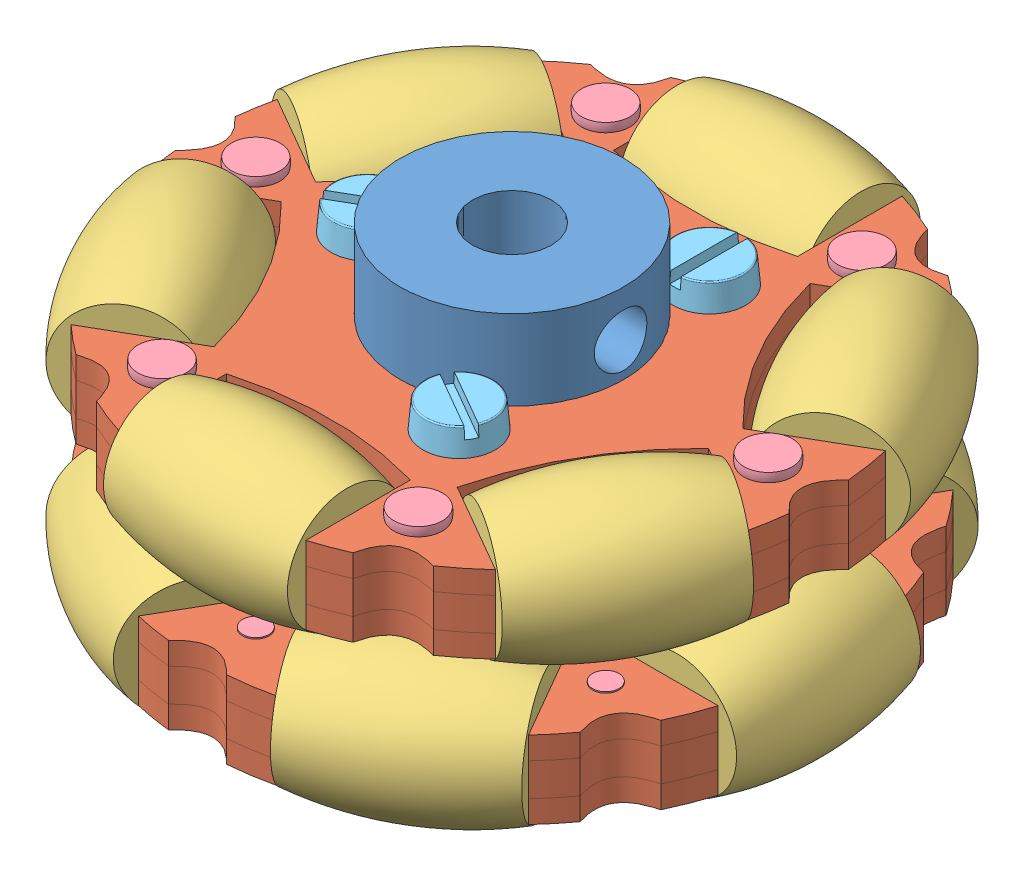
SolidWorks assembly 2寸全向轮1, configuration 默认. Lengths in mm.
Overall size (65.85 26.41 65.85).
35 component instances, 5 part files, 14 mates.
Components (placement in the parent):
- 法兰（新）-1: 法兰（新） [默认] at (1.0243 -5.9767 28) size (28 22 28)
- 2mm全向轮-1: 2mm全向轮 [默认] at (11.1029 12.5733 31.6277) x (0.866025 0 0.5) z (0 1 0) size (52.67 52.62 13.52)
  - 2mm全向轮片1-1: 2mm全向轮片1 [默认] at (-10.5422 -1.8976 -13.55) x (0 -1 0) z (0 0 1) size (47.34 45.39 5.9)
  - 从动-1: 从动 [默认] at (-10.1553 -1.8976 -5.0249) x (0 -1 0) z (0.265082 0 0.964226) size (14 11 11)
  - 从动-13: 从动 [默认] at (-10.3488 -2.2327 -5.0249) x (-0.866025 -0.5 0) z (0.132541 -0.229568 0.964226) size (14 11 11)
  - 从动-14: 从动 [默认] at (-10.7357 -2.2327 -5.0249) x (-0.866025 0.5 0) z (-0.132541 -0.229568 0.964226) size (14 11 11)
  - 从动-15: 从动 [默认] at (-10.9291 -1.8976 -5.0249) x (0 1 0) z (-0.265082 0 0.964226) size (14 11 11)
  - 从动-16: 从动 [默认] at (-10.7357 -1.5625 -5.0249) x (0.866025 0.5 0) z (-0.132541 0.229568 0.964226) size (14 11 11)
  - 从动-17: 从动 [默认] at (-10.3488 -1.5625 -5.0249) x (0.866025 -0.5 0) z (0.132541 0.229568 0.964226) size (14 11 11)
- 2mm全向轮-2: 2mm全向轮 [默认] at (7.9388 1.6733 36.181) x (0.5 0 0.866025) z (0 1 0) size (52.67 52.62 13.52)
  - 2mm全向轮片1-1: 2mm全向轮片1 [默认] at (-10.5422 -1.8976 -13.55) x (0 -1 0) z (0 0 1) size (47.34 45.39 5.9)
  - 从动-1: 从动 [默认] at (-10.1553 -1.8976 -5.0249) x (0 -1 0) z (0.265082 0 0.964226) size (14 11 11)
  - 从动-13: 从动 [默认] at (-10.3488 -2.2327 -5.0249) x (-0.866025 -0.5 0) z (0.132541 -0.229568 0.964226) size (14 11 11)
  - 从动-14: 从动 [默认] at (-10.7357 -2.2327 -5.0249) x (-0.866025 0.5 0) z (-0.132541 -0.229568 0.964226) size (14 11 11)
  - 从动-15: 从动 [默认] at (-10.9291 -1.8976 -5.0249) x (0 1 0) z (-0.265082 0 0.964226) size (14 11 11)
  - 从动-16: 从动 [默认] at (-10.7357 -1.5625 -5.0249) x (0.866025 0.5 0) z (-0.132541 0.229568 0.964226) size (14 11 11)
  - 从动-17: 从动 [默认] at (-10.3488 -1.5625 -5.0249) x (0.866025 -0.5 0) z (0.132541 0.229568 0.964226) size (14 11 11)
- thin head rivets gb-1: thin head rivets gb [GB_CONNECTING_PIECE_RIVET_THR 2X6] at (17.9118 -12.5567 18.25) x (0 1 0) z (-0.99315 0 -0.116849) size (6.68 3.74 3.74)
- thin head rivets gb-3: thin head rivets gb [GB_CONNECTING_PIECE_RIVET_THR 2X6] at (17.9118 -12.5567 37.75) x (0 1 0) z (-0.395381 0 -0.918517) size (6.68 3.74 3.74)
- thin head rivets gb-4: thin head rivets gb [GB_CONNECTING_PIECE_RIVET_THR 2X6] at (1.0243 -12.5567 47.5) x (0 1 0) z (0.597769 0 -0.801668) size (6.68 3.74 3.74)
- thin head rivets gb-5: thin head rivets gb [GB_CONNECTING_PIECE_RIVET_THR 2X6] at (-15.8632 -12.5567 37.75) x (0 1 0) z (0.99315 0 0.116849) size (6.68 3.74 3.74)
- thin head rivets gb-6: thin head rivets gb [GB_CONNECTING_PIECE_RIVET_THR 2X6] at (-15.8632 -12.5567 18.25) x (0 1 0) z (0.395381 0 0.918517) size (6.68 3.74 3.74)
- thin head rivets gb-7: thin head rivets gb [GB_CONNECTING_PIECE_RIVET_THR 2X6] at (1.0243 -12.5567 8.5) x (0 1 0) z (-0.597769 0 0.801668) size (6.68 3.74 3.74)
- thin head rivets gb-9: thin head rivets gb [GB_CONNECTING_PIECE_RIVET_THR 2X6] at (-18.4757 5.6033 28) x (0 -1 0) z (-0.795368 0 -0.606127) size (6.68 3.74 3.74)
- thin head rivets gb-11: thin head rivets gb [GB_CONNECTING_PIECE_RIVET_THR 2X6] at (-8.7257 5.6033 11.1125) x (0 -1 0) z (0.127237 0 -0.991872) size (6.68 3.74 3.74)
- thin head rivets gb-12: thin head rivets gb [GB_CONNECTING_PIECE_RIVET_THR 2X6] at (10.7743 5.6033 11.1125) x (0 -1 0) z (0.922605 0 -0.385745) size (6.68 3.74 3.74)
- thin head rivets gb-13: thin head rivets gb [GB_CONNECTING_PIECE_RIVET_THR 2X6] at (20.5243 5.6033 28) x (0 -1 0) z (0.795368 0 0.606127) size (6.68 3.74 3.74)
- thin head rivets gb-14: thin head rivets gb [GB_CONNECTING_PIECE_RIVET_THR 2X6] at (10.7743 5.6033 44.8875) x (0 -1 0) z (-0.127237 0 0.991872) size (6.68 3.74 3.74)
- thin head rivets gb-15: thin head rivets gb [GB_CONNECTING_PIECE_RIVET_THR 2X6] at (-8.7257 5.6033 44.8875) x (0 -1 0) z (-0.922605 0 0.385745) size (6.68 3.74 3.74)
- slotted cheese head screw_iso-1: slotted cheese head screw_iso [ISO 1207 - M3 x 10 - 10N] at (6.5243 6.9233 18.4737) x (0 -1 0) z (0 0 1) size (12.01 5.5 5.5)
- slotted cheese head screw_iso-2: slotted cheese head screw_iso [ISO 1207 - M3 x 10 - 10N] at (6.5243 6.9233 37.5263) x (0 -1 0) z (-0.866025 0 -0.5) size (12.01 5.5 5.5)
- slotted cheese head screw_iso-3: slotted cheese head screw_iso [ISO 1207 - M3 x 10 - 10N] at (-9.9757 6.9233 28) x (0 -1 0) z (0.866025 0 -0.5) size (12.01 5.5 5.5)
- slotted cheese head screw_iso-4: slotted cheese head screw_iso [ISO 1207 - M3 x 10 - 10N] at (10.5506 -13.8767 22.5) x (0 1 0) z (0.694913 0 -0.719094) size (12.01 5.5 5.5)
- slotted cheese head screw_iso-6: slotted cheese head screw_iso [ISO 1207 - M3 x 10 - 10N] at (1.0243 -13.8767 39) x (0 1 0) z (0.275298 0 0.961359) size (12.01 5.5 5.5)
- slotted cheese head screw_iso-7: slotted cheese head screw_iso [ISO 1207 - M3 x 10 - 10N] at (-8.502 -13.8767 22.5) x (0 1 0) z (-0.97021 0 -0.242265) size (12.01 5.5 5.5)
Mates (geometry in assembly coordinates):
- 同心1: concentric anti-aligned: cylinder of 法兰（新）-1 through (1.0243 -10.9767 28) axis (0 1 0) radius 8.5; cylinder of 2mm全向轮-1/2mm全向轮片1-1 through (1.0243 3.2233 28) axis (0 -1 0) radius 8.5
- 重合1: coincident anti-aligned: plane of 法兰（新）-1 through (1.0243 -0.9767 28) normal (0 1 0); plane of 2mm全向轮-1/2mm全向轮片1-1 through (1.0243 -0.9767 28) normal (0 -1 0)
- 同心2: concentric aligned: cylinder of 法兰（新）-1 through (6.5243 -0.9767 18.4737) axis (0 -1 0) radius 1.5; cylinder of 2mm全向轮-1/2mm全向轮片1-1 through (6.5243 9.0233 18.4737) axis (0 -1 0) radius 1.5
- 同心3: concentric anti-aligned: cylinder of 法兰（新）-1 through (1.0243 -10.9767 28) axis (0 1 0) radius 8.5; cylinder of 2mm全向轮-2/2mm全向轮片1-1 through (1.0243 -7.6767 28) axis (0 -1 0) radius 8.5
- 重合2: coincident anti-aligned: plane of 法兰（新）-1 through (1.0243 -5.9767 28) normal (0 -1 0); plane of 2mm全向轮-2/2mm全向轮片1-1 through (1.0243 -5.9767 28) normal (0 1 0)
- 同心6: concentric anti-aligned: cylinder of 2mm全向轮-2/2mm全向轮片1-1 through (17.9118 -26.4767 18.25) axis (0 1 0) radius 1; cylinder of thin head rivets gb-1 through (17.9118 -14.875 18.25) axis (0 -1 0) radius 1
- 重合4: coincident anti-aligned: plane of 2mm全向轮-2/2mm全向轮片1-1 through (1.0243 -11.8767 28) normal (0 -1 0); plane of thin head rivets gb-1 through (18.1267 -11.8767 16.4238) normal (0 1 0)
- 同心7: concentric aligned: cylinder of 法兰（新）-1 through (-8.502 -0.9767 22.5) axis (0 -1 0) radius 1.5; cylinder of 2mm全向轮-2/2mm全向轮片1-1 through (-8.502 -1.8767 22.5) axis (0 -1 0) radius 1.5
- 同心9: concentric aligned: cylinder of 2mm全向轮-1/2mm全向轮片1-1 through (-18.4757 -15.5767 28) axis (0 1 0) radius 1; cylinder of thin head rivets gb-9 through (-18.4757 7.9215 28) axis (0 1 0) radius 1
- 重合5: coincident anti-aligned: plane of 2mm全向轮-1/2mm全向轮片1-1 through (1.0243 4.9233 28) normal (0 1 0); plane of thin head rivets gb-9 through (-19.5902 4.9233 29.4625) normal (0 -1 0)
- 同心10: concentric anti-aligned: cylinder of 2mm全向轮-1/2mm全向轮片1-1 through (6.5243 9.0233 18.4737) axis (0 -1 0) radius 1.5; cylinder of slotted cheese head screw_iso-1 through (6.5243 32.3233 18.4737) axis (0 1 0) radius 1.5
- 重合6: coincident anti-aligned: plane of 2mm全向轮-1/2mm全向轮片1-1 through (1.0243 4.9233 28) normal (0 1 0); plane of slotted cheese head screw_iso-1 through (8.0243 4.9233 18.4737) normal (0 -1 0)
- 同心11: concentric aligned: cylinder of 2mm全向轮-2/2mm全向轮片1-1 through (10.5506 -1.8767 22.5) axis (0 -1 0) radius 1.5; cylinder of slotted cheese head screw_iso-4 through (10.5506 -39.2767 22.5) axis (0 -1 0) radius 1.5
- 重合7: coincident anti-aligned: plane of 2mm全向轮-2/2mm全向轮片1-1 through (1.0243 -11.8767 28) normal (0 -1 0); plane of slotted cheese head screw_iso-4 through (11.6292 -11.8767 23.5424) normal (0 1 0)
